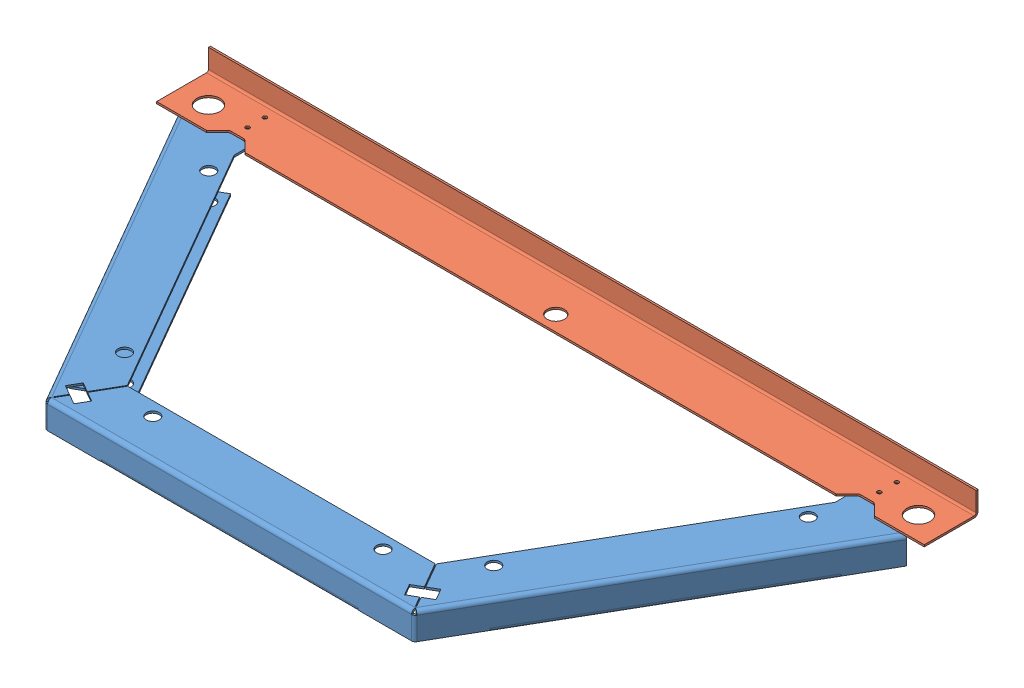
SolidWorks assembly GE-16007_ASM, configuration Default. Lengths in mm.
Overall size (1270 85.8 603.25).
2 component instances, 2 part files, 0 mates.
Components (placement in the parent):
- GE-16007-01-1: GE-16007-01 [Default] at origin size (1206.5 48.01 590.55)
- GE-16007-02-1: GE-16007-02 [Default] at (0 3.175 -599.9988) x (1 0 0) z (0 1 0) size (1270 88.9 38.1)
